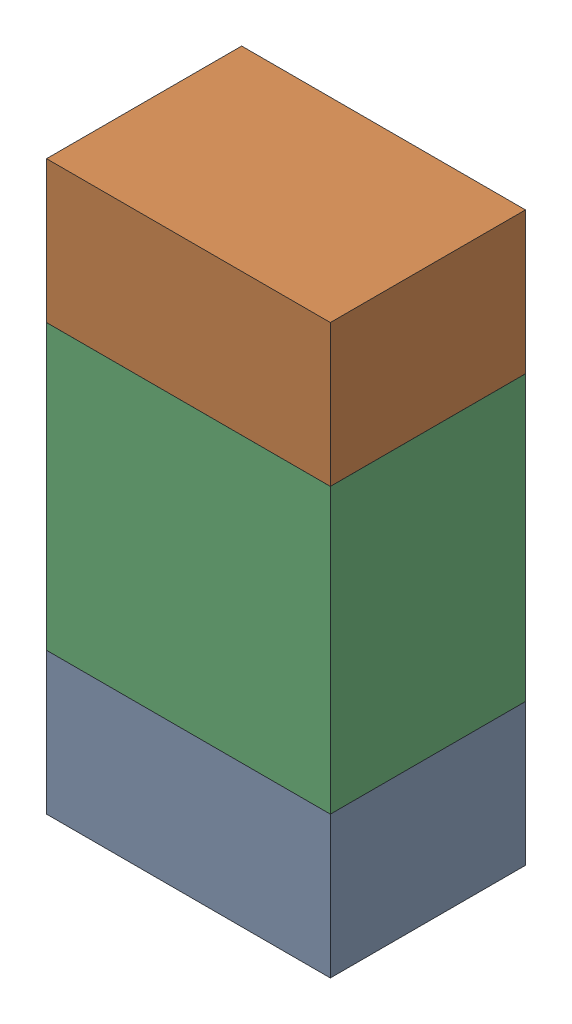
SolidWorks assembly R29, configuration ﾃﾞﾌｫﾙﾄ. Lengths in mm.
Overall size (0.8 1.6 0.55).
6 component instances, 2 part files, 0 mates.
Components (placement in the parent):
- 689261784-1: 689261784 [ﾃﾞﾌｫﾙﾄ] at (22.4999 69.1501 0) size (0.8 0.4 0.55)
  - Extruded_34-1: Extruded_34 [ﾃﾞﾌｫﾙﾄ] at origin size (0.8 0.4 0.55)
- 689261784-2: 689261784 [ﾃﾞﾌｫﾙﾄ] at (22.4999 70.3501 0) size (0.8 0.4 0.55)
  - Extruded_34-1: Extruded_34 [ﾃﾞﾌｫﾙﾄ] at origin size (0.8 0.4 0.55)
- 689261648-1: 689261648 [ﾃﾞﾌｫﾙﾄ] at (22.4999 69.75 0) size (0.8 0.8 0.55)
  - Extruded_33-1: Extruded_33 [ﾃﾞﾌｫﾙﾄ] at origin size (0.8 0.8 0.55)
